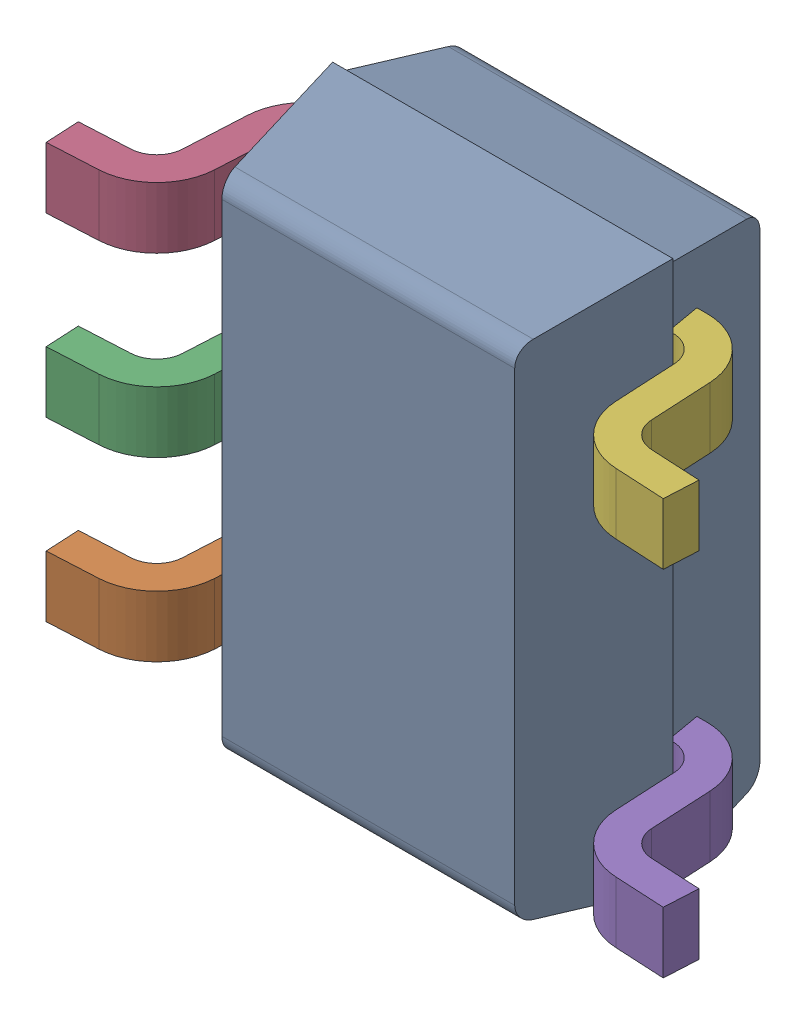
SolidWorks assembly U307_1PCB, configuration Default. Lengths in mm.
Overall size (2.28 2 0.95).
8 component instances, 6 part files, 0 mates.
Components (placement in the parent):
- DCK0005AakaMAA05A-1: DCK0005AakaMAA05A [Default] at (132.6001 116.9999 -2.1938) x (0 -1 0) z (-1 0 0) size (2 0.95 2.28)
  - BODY_MAA05-1: BODY_MAA05 [Default] at origin size (2 0.9 1.25)
  - LEADS_MAA05A-1: LEADS_MAA05A [Default] at (0.65 0 0) x (0 0 1) z (1 0 0) size (2.28 0.67 1.53)
    - LEADS_MAA05A_3-1: LEADS_MAA05A_3 [Default] at origin size (0.55 0.67 0.23)
    - LEADS_MAA05A_4-1: LEADS_MAA05A_4 [Default] at origin size (0.55 0.67 0.23)
    - LEADS_MAA05A_5-1: LEADS_MAA05A_5 [Default] at origin size (0.55 0.67 0.23)
    - LEADS_MAA05A_6-1: LEADS_MAA05A_6 [Default] at origin size (0.55 0.67 0.23)
    - LEADS_MAA05A_7-1: LEADS_MAA05A_7 [Default] at origin size (0.55 0.67 0.23)
